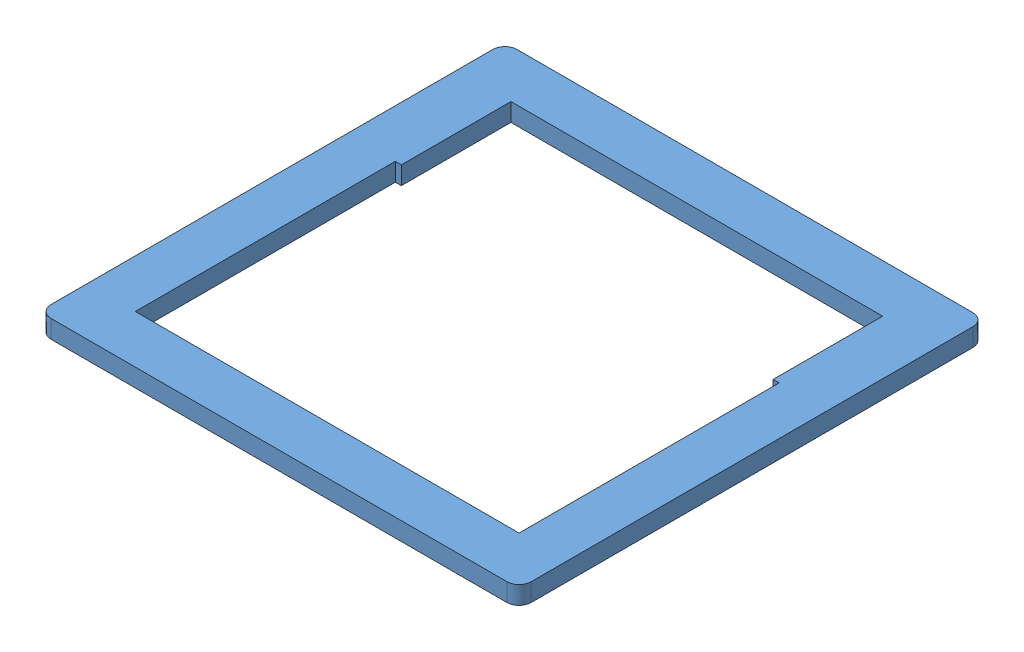
SolidWorks assembly PAD, configuration 默认. Lengths in mm.
Overall size (79.7 3 77.35).
5 component instances, 5 part files, 0 mates.
Components (placement in the parent):
- 定位板-1: 定位板 [默认] at (-112.2485 -60.8015 179.3036) x (1 0 0) z (0 -1 0) size (63.7 43.05 3) (hidden)
- 定位板外包覆-1: 定位板外包覆 [默认] at (-83.1087 -63.8015 199.7694) size (79.7 3 77.35)
- 底层1-1: 底层1 [默认] at (-161.6806 5752.5401 301.1317) size (79.7 2 77.35) (hidden)
- 底层2-1: 底层2 [默认] at (113.3921 3018.4732 237.9473) size (77.7 2 75.35) (hidden)
- 底层3-1: 底层3 [默认] at (129.6412 2421.7881 243.9405) size (75.7 2 73.35) (hidden)
